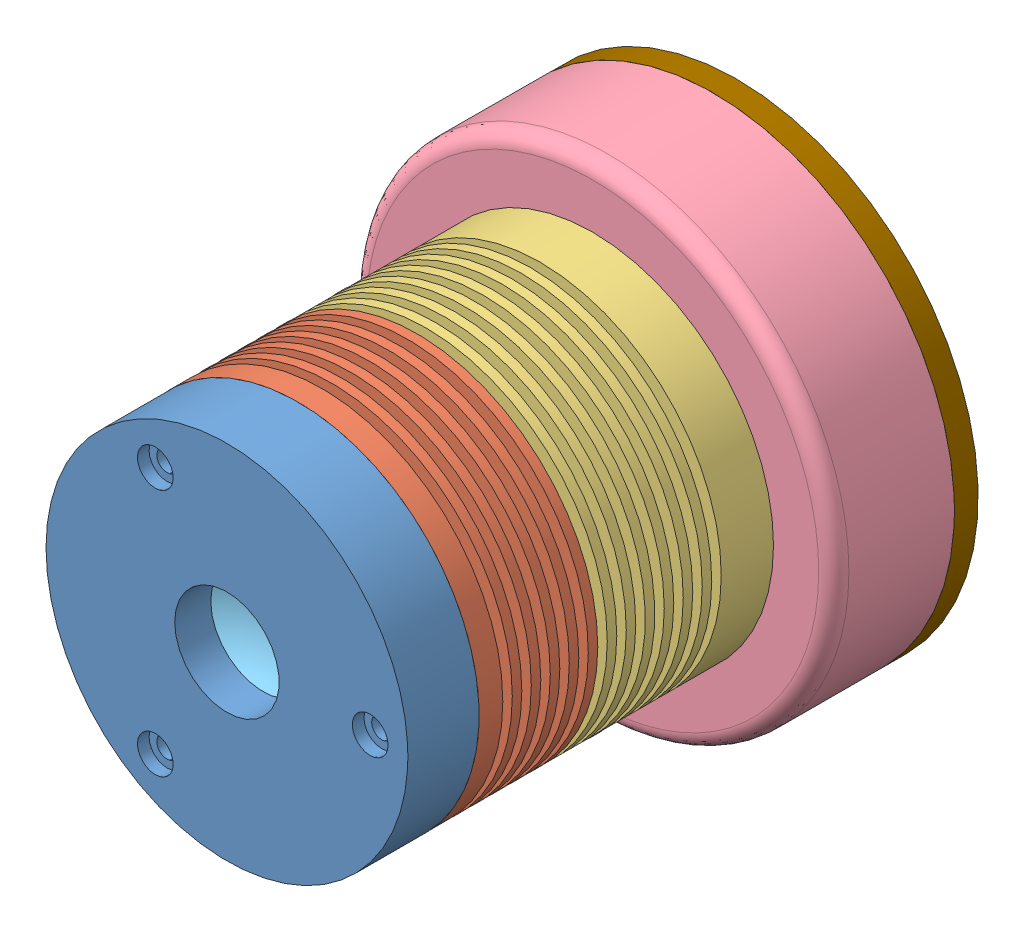
SolidWorks assembly Assemblage version 2, configuration Défaut. Lengths in mm.
Overall size (132.77 132.77 107.4).
9 component instances, 9 part files, 18 mates.
Components (placement in the parent):
- pièce de support de lentille V.0.3-1: pièce de support de lentille V.0.3 [Défaut] at (-29.1782 -8.1326 68.7) size (76.2 76.2 15)
- pièce no1 avec ailettes V.0.3-1: pièce no1 avec ailettes V.0.3 [Défaut] at (17.5136 -29.3675 68.7) x (-1 0 0) z (0 0 -1) size (76.2 76.2 27)
- pièce no2 milieu avec trous aluminium V.0.3-1: pièce no2 milieu avec trous aluminium V.0.3 [Défaut] at (-37.9058 -14.3155 6.7) size (76.2 76.2 35)
- support PCB-1: support PCB [Défaut] at (-6.1659 0.3032 -18.7) size (101.6 101.6 25.42)
- LC2679-Solidworks-1: LC2679-Solidworks [Default] at (-6.1659 0.3032 70.5942) size (25.4 25.4 7.26)
- NE2R30B-Solidworks-1: NE2R30B-Solidworks [Default] at (-6.1659 0.3032 37.755) x (0 0 -1) z (1 0 0) size (2.11 50.8 50.8)
- pièce imprimé 3D_intersection V.0.2-1: pièce imprimé 3D_intersection V.0.2 [Défaut] at (-22.7911 -6.8055 -3.3) size (50.8 50.8 35)
- pièce imprimé 3D_socket-1: pièce imprimé 3D_socket [Défaut] at (-22.7911 -6.8055 -8.3) size (50.8 50.8 10)
- embout avec logo-1: embout avec logo [Défaut] at (-6.1659 0.3032 -18.7) x (-0.923728 -0.383049 0) z (0 0 -1) size (101.6 101.6 5)
Mates (geometry in assembly coordinates):
- Coïncidente1: coincident anti-aligned: plane of pièce de support de lentille V.0.3-1 through (-6.1659 0.3032 68.7) normal (0 0 -1); plane of pièce no1 avec ailettes V.0.3-1 through (-6.1659 0.3032 68.7) normal (0 0 1)
- Coaxiale1: concentric anti-aligned: cylinder of pièce de support de lentille V.0.3-1 through (-6.1659 0.3032 83.7) axis (0 0 -1) radius 38.1; cylinder of pièce no1 avec ailettes V.0.3-1 through (-6.1659 0.3032 41.7) axis (0 0 1) radius 38.1
- Coaxiale2: concentric aligned: cylinder of pièce de support de lentille V.0.3-1 through (23.9966 0.3032 83.7) axis (0 0 1) radius 2.1526; cylinder of pièce no1 avec ailettes V.0.3-1 through (23.9966 0.3032 68.7) axis (0 0 1) radius 1.8986
- Coïncidente2: coincident anti-aligned: plane of pièce de support de lentille V.0.3-1 through (-6.1659 0.3032 76.1) normal (0 0 -1); circle of LC2679-Solidworks-1
- Coïncidente3: coincident anti-aligned: cylinder of pièce de support de lentille V.0.3-1 through (-6.1659 0.3032 76.1) axis (0 0 -1) radius 12.7; circle of LC2679-Solidworks-1
- Coïncidente4: coincident anti-aligned: plane of pièce no2 milieu avec trous aluminium V.0.3-1 through (-6.1659 0.3032 36.7) normal (0 0 1); plane of NE2R30B-Solidworks-1 through (-6.1659 0.3032 36.7) normal (0 0 -1)
- Coaxiale5: concentric aligned: cylinder of pièce no2 milieu avec trous aluminium V.0.3-1 through (-6.1659 0.3032 36.7) axis (0 0 1) radius 25.4; cylinder of NE2R30B-Solidworks-1 through (-6.1659 0.3032 38.81) axis (0 0 1) radius 25.4
- Coïncidente5: coincident anti-aligned: plane of pièce no1 avec ailettes V.0.3-1 through (-6.1659 0.3032 41.7) normal (0 0 -1); plane of pièce no2 milieu avec trous aluminium V.0.3-1 through (-6.1659 0.3032 41.7) normal (0 0 1)
- Coaxiale6: concentric anti-aligned: cylinder of pièce no1 avec ailettes V.0.3-1 through (-6.1659 0.3032 41.7) axis (0 0 1) radius 38.1; cylinder of pièce no2 milieu avec trous aluminium V.0.3-1 through (-6.1659 0.3032 41.7) axis (0 0 -1) radius 38.1
- Parallèle1: parallel anti-aligned: cylinder of pièce no1 avec ailettes V.0.3-1 through (23.9966 0.3032 68.7) axis (0 0 1) radius 1.8986; cylinder of pièce no2 milieu avec trous aluminium V.0.3-1 through (23.9916 0.3032 6.7) axis (0 0 -1) radius 1.8986
- Coïncidente6: coincident anti-aligned: plane of pièce no2 milieu avec trous aluminium V.0.3-1 through (-6.1659 0.3032 31.7) normal (0 0 -1); plane of pièce imprimé 3D_intersection V.0.2-1 through (-6.1659 0.3032 31.7) normal (0 0 1)
- Coaxiale8: concentric aligned: cylinder of pièce no2 milieu avec trous aluminium V.0.3-1 through (-6.1659 0.3032 110.7871) axis (0 0 -1) radius 26.1937; cylinder of pièce imprimé 3D_intersection V.0.2-1 through (-6.1659 0.3032 21.7) axis (0 0 -1) radius 25.4
- Coïncidente7: coincident anti-aligned: plane of pièce imprimé 3D_intersection V.0.2-1 through (-6.1659 0.3032 -3.3) normal (0 0 -1); plane of pièce imprimé 3D_socket-1 through (-6.1659 0.3032 -3.3) normal (0 0 1)
- Coaxiale9: concentric aligned: cylinder of pièce imprimé 3D_intersection V.0.2-1 through (-6.1659 0.3032 21.7) axis (0 0 -1) radius 25.4; cylinder of pièce imprimé 3D_socket-1 through (-6.1659 0.3032 -3.3) axis (0 0 -1) radius 25.4
- Coïncidente8: coincident anti-aligned: plane of pièce no2 milieu avec trous aluminium V.0.3-1 through (-6.1659 0.3032 6.7) normal (0 0 -1); plane of support PCB-1 through (-6.1659 0.3032 6.7) normal (0 0 1)
- Coaxiale10: concentric aligned: cylinder of pièce no2 milieu avec trous aluminium V.0.3-1 through (-6.1659 0.3032 41.7) axis (0 0 -1) radius 38.1; cylinder of support PCB-1 through (-6.1659 0.3032 6.7) axis (0 0 -1) radius 50.8
- Coïncidente9: coincident anti-aligned: plane of support PCB-1 through (-6.1659 0.3032 -18.7) normal (0 0 -1); plane of embout avec logo-1 through (-6.1659 0.3032 -18.7) normal (0 0 1)
- Coaxiale11: concentric anti-aligned: cylinder of support PCB-1 through (-6.1659 0.3032 6.7) axis (0 0 -1) radius 50.8; cylinder of embout avec logo-1 through (-6.1659 0.3032 -23.7) axis (0 0 1) radius 50.8
